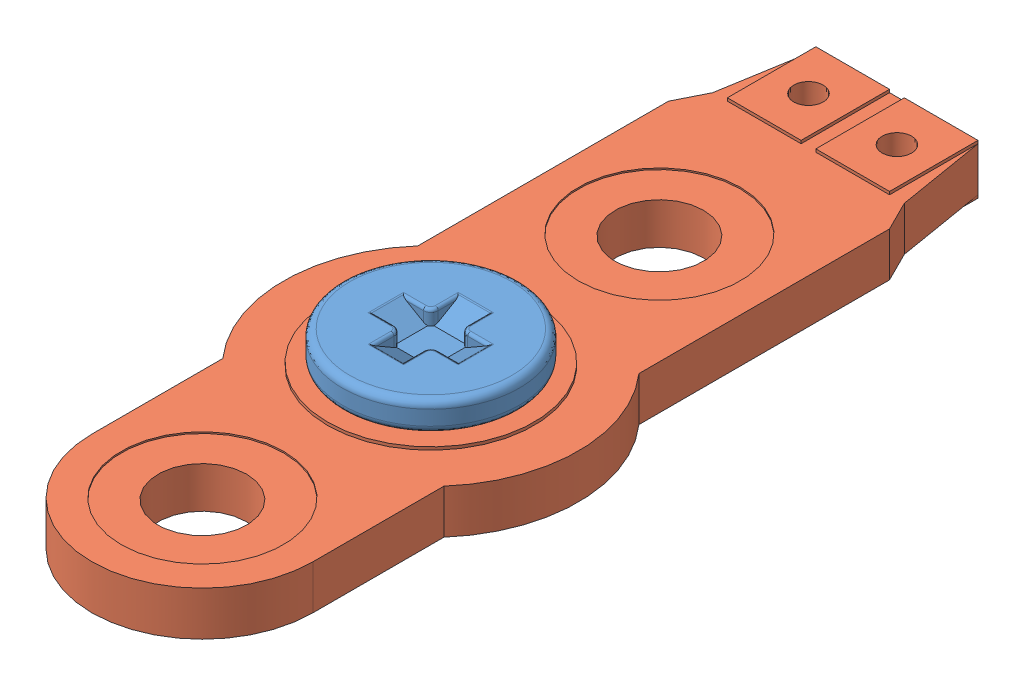
SolidWorks assembly screw switch, configuration Default. Lengths in mm.
Overall size (10 4.5 27.31).
2 component instances, 2 part files, 6 mates.
Components (placement in the parent):
- screw switch screw-1: screw switch screw [Default] at (0 2.6 0) size (6 4.5 6)
- screw switch switch-1: screw switch switch [Default] at origin size (10 3.1 27.31)
Mates (geometry in assembly coordinates):
- Coincident1: coincident anti-aligned: plane of screw switch switch-1 through (0 0 7.75) normal (0 -1 0)
- Coincident2: coincident: point of screw switch switch-1
- Coincident3: coincident: unknown of screw switch switch-1
- Parallel1: parallel aligned: plane of screw switch switch-1 through (3.75 1.5 7.75) normal (1 0 0)
- Concentric2: concentric: cylinder of screw switch screw-1 through (0 -214.6459 0) axis (0 -1 0) radius 1.25; cylinder of screw switch switch-1 through (0 1.5 0) axis (0 -1 0) radius 1.5
- Coincident5: coincident anti-aligned: plane of screw switch screw-1 through (3 1.6 0) normal (0 -1 0); plane of screw switch switch-1 through (0 1.6 0) normal (0 1 0)
